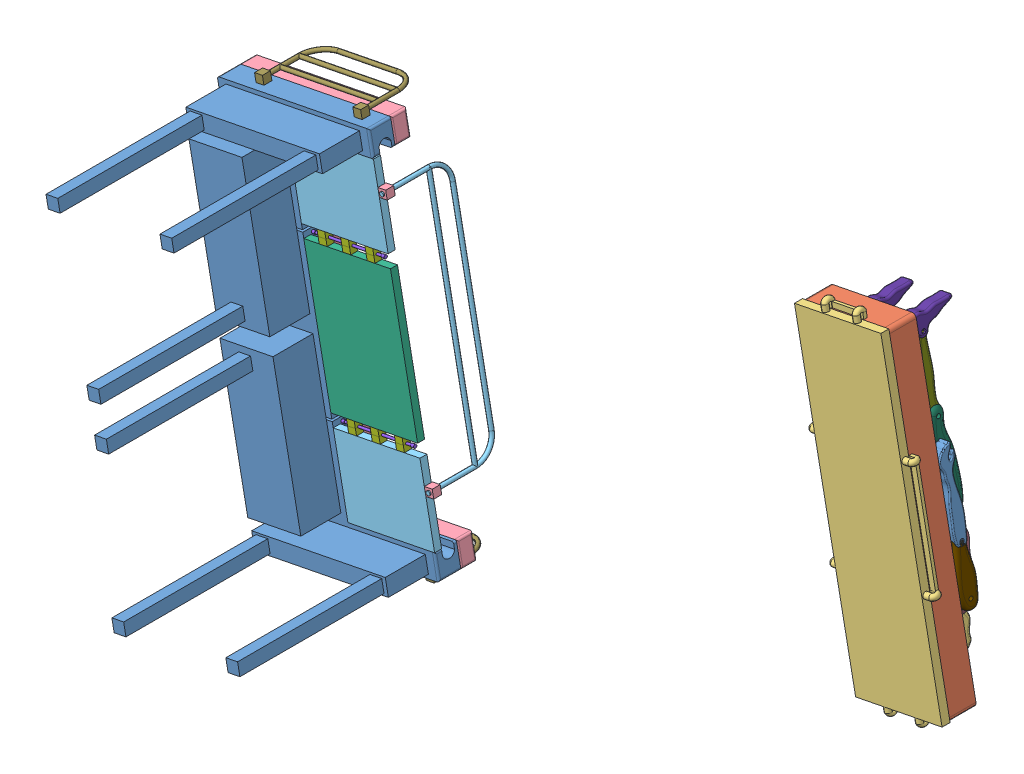
SolidWorks assembly Main_Bed_New, configuration Default. Lengths in mm.
Overall size (4670.43 3031.29 1745.74).
54 component instances, 23 part files, 74 mates.
Components (placement in the parent):
- Bed Matt-1: Bed Matt [Default] at (-2427.7538 2720.2704 -241.3) x (0.981103 0.193488 0) z (0 0 1) size (977.9 2311.4 1308.1)
- Strecher-1: Strecher [Default] at (1211.9857 3282.7447 -241.3) x (0.981103 0.193488 0) z (0 0 1) size (558.8 2006.6 169.05)
- Stretcher Plate-4: Stretcher Plate [Default] at (1600.2382 1314.064 -21.45) x (0.981103 0.193488 0) z (0 0 -1) size (724.37 2140.75 113.2)
- Bed Matteress-1: Bed Matteress [Default] at (-2427.7538 2720.2704 -241.3) x (0.981103 0.193488 0) z (0 0 1) size (977.9 2311.4 101.6)
- Bed_Plate_Small-1: Bed_Plate_Small [Default] at (-1692.2108 1156.6406 -44.45) x (0.981103 0.193488 0) z (0 0 1) size (560.57 482.6 44.45)
- Bed_Plate_Small-2: Bed_Plate_Small [Default] at (-1987.0861 2651.8411 -44.45) x (0.981103 0.193488 0) z (0 0 1) size (560.57 482.6 44.45)
- Bed_Plate_Large-1: Bed_Plate_Large [Default] at (-1878.9651 2103.6009 -44.45) x (0.981103 0.193488 0) z (0 0 1) size (560.57 889 44.45)
- Bed_Hinge-2: Bed_Hinge [Default] at (-1551.6324 1223.1985 0.01) x (0 0 -1) z (-0.981103 -0.193488 0) size (44.46 38.1 50.8)
- Bed_Hinge-3: Bed_Hinge [Default] at (-1601.4724 1213.3694 0.01) x (0 0 -1) z (0.981103 0.193488 0) size (44.46 38.1 50.8)
- Bed_Hinge-6: Bed_Hinge [Default] at (-1297.5562 1273.3061 0.01) x (0 0 -1) z (0.981103 0.193488 0) size (44.46 38.1 50.8)
- Bed_Hinge-7: Bed_Hinge [Default] at (-1247.7162 1283.1352 0.01) x (0 0 -1) z (-0.981103 -0.193488 0) size (44.46 38.1 50.8)
- Bed_Hinge-12: Bed_Hinge [Default] at (-1451.4787 1242.9503 0.01) x (0 0 -1) z (0.981103 0.193488 0) size (44.46 38.1 50.8)
- Bed_Hinge-13: Bed_Hinge [Default] at (-1401.6387 1252.7795 0.01) x (0 0 -1) z (-0.981103 -0.193488 0) size (44.46 38.1 50.8)
- Hinge Rod-1: Hinge Rod [Default] at (-1213.9368 1289.797 -22.22) x (0.177246 -0.898749 0.401041) z (0.981103 0.193488 0) size (20 20 470)
- Hinge Rod-2: Hinge Rod [Default] at (-1822.5654 2153.5576 -22.22) x (-0.177246 0.898749 0.401041) z (-0.981103 -0.193488 0) size (20 20 470)
- Bed_Hinge-14: Bed_Hinge [Default] at (-1738.3867 2170.1589 0.01) x (0 0 -1) z (-0.981103 -0.193488 0) size (44.46 38.1 50.8)
- Bed_Hinge-15: Bed_Hinge [Default] at (-1788.2268 2160.3297 0.01) x (0 0 -1) z (0.981103 0.193488 0) size (44.46 38.1 50.8)
- Bed_Hinge-16: Bed_Hinge [Default] at (-1588.3931 2199.7398 0.01) x (0 0 -1) z (-0.981103 -0.193488 0) size (44.46 38.1 50.8)
- Bed_Hinge-17: Bed_Hinge [Default] at (-1638.2331 2189.9106 0.01) x (0 0 -1) z (0.981103 0.193488 0) size (44.46 38.1 50.8)
- Bed_Hinge-18: Bed_Hinge [Default] at (-1434.4706 2230.0956 0.01) x (0 0 -1) z (-0.981103 -0.193488 0) size (44.46 38.1 50.8)
- Bed_Hinge-19: Bed_Hinge [Default] at (-1484.3106 2220.2664 0.01) x (0 0 -1) z (0.981103 0.193488 0) size (44.46 38.1 50.8)
- Roller_Small_Plate-1: Roller_Small_Plate [Default] at (-1548.0613 1392.1829 -40.4983) x (0.525896 0.103714 0.844202) z (-0.193488 0.981103 0) size (38.1 38.1 762)
- Roller_Small_Plate-2: Roller_Small_Plate [Default] at (-1639.7944 1374.0917 -40.4983) x (0.900265 0.177545 -0.397493) z (-0.193488 0.981103 0) size (38.1 38.1 762)
- Roller_Small_Plate-3: Roller_Small_Plate [Default] at (-1365.0169 1428.2819 -40.4983) x (-0.124546 -0.024562 -0.99191) z (-0.193488 0.981103 0) size (38.1 38.1 762)
- Roller_Small_Plate-4: Roller_Small_Plate [Default] at (-1273.2838 1446.373 -40.4983) x (0.980896 0.193447 -0.020528) z (-0.193488 0.981103 0) size (38.1 38.1 762)
- Roller_Big Plate-5: Roller_Big Plate [Default] at (-1831.4633 2345.9721 -40.4963) x (0.98109 0.193485 -0.005115) z (-0.193488 0.981103 0) size (38.1 38.1 304.8)
- Roller_Big Plate-6: Roller_Big Plate [Default] at (-1739.7302 2364.0632 -40.4963) x (0.98109 0.193485 -0.005115) z (-0.193488 0.981103 0) size (38.1 38.1 304.8)
- Roller_Big Plate-7: Roller_Big Plate [Default] at (-1464.9528 2418.2533 -40.4963) x (0.980987 0.193465 -0.015372) z (-0.193488 0.981103 0) size (38.1 38.1 304.8)
- Roller_Big Plate-8: Roller_Big Plate [Default] at (-1556.6859 2400.1622 -40.4963) x (0.980633 0.193395 -0.03093) z (-0.193488 0.981103 0) size (38.1 38.1 304.8)
- Roller_Big Plate-9: Roller_Big Plate [Default] at (-1536.588 850.7716 -40.4963) x (0.980896 0.193447 -0.020528) z (-0.193488 0.981103 0) size (38.1 38.1 304.8)
- Roller_Big Plate-10: Roller_Big Plate [Default] at (-1444.8549 868.8627 -40.4963) x (0.801443 0.158056 -0.576808) z (-0.193488 0.981103 0) size (38.1 38.1 304.8)
- Roller_Big Plate-11: Roller_Big Plate [Default] at (-1261.8106 904.9617 -40.4963) x (0.980778 0.193424 -0.025712) z (-0.193488 0.981103 0) size (38.1 38.1 304.8)
- Roller_Big Plate-12: Roller_Big Plate [Default] at (-1170.0775 923.0528 -40.4963) x (0.980778 0.193424 -0.025712) z (-0.193488 0.981103 0) size (38.1 38.1 304.8)
- Bed_Side_Handle-1: Bed_Side_Handle [Default] at (-2095.4954 904.2402 -100.8) x (-0.193488 0.981103 0) z (-0.981103 -0.193488 0) size (1574.8 393.7 50.8)
- Bed_Side_Handle_Small-1: Bed_Side_Handle_Small [Default] at (-2211.5278 2788.8026 -100.8) x (0.981103 0.193488 0) z (-0.193488 0.981103 0) size (685.8 393.7 50.8)
- Bed_Side_Handle_Small-2: Bed_Side_Handle_Small [Default] at (-1754.471 471.2418 -100.8) x (0.981103 0.193488 0) z (-0.193488 0.981103 0) size (685.8 393.7 50.8)
- Human_3D(10-04-12)-1: Human_3D(10-04-12) [Default] at (1738.9169 2054.8964 -241.3) x (0.981103 0.193488 0) z (0 0 -1) size (530.68 1832.11 366.32)
  - Chest_3D-1: Chest_3D [Default] at (-194.0697 -37.8635 128.1318) size (350.02 515.24 294.39)
  - Abdominal_3D-1: Abdominal_3D [Default] at (-147.423 -255.9077 128.1318) size (309.81 426.95 250.71)
  - Thigh_3D-1: Thigh_3D [Default] at (76.9303 -255.9077 128.1318) size (116.78 669.36 281.34)
  - Thigh_3D-2: Thigh_3D [Default] at (-173.0697 -255.9077 128.1318) size (116.78 669.36 281.34)
  - Leg_3D-1: Leg_3D [Default] at (-124.0697 -1124.992 128.1318) size (61.6 568.33 179.47)
  - Leg_3D-2: Leg_3D [Default] at (125.9303 -1124.992 128.1318) size (61.6 568.33 179.47)
  - Foot_3D-1: Foot_3D [Default] at (86.9303 -1224.992 128.1318) size (197.99 220.93 341.64)
  - Foot_3D-2: Foot_3D [Default] at (-163.0697 -1224.992 128.1318) size (197.99 220.93 341.64)
  - Arm_3D-1: Arm_3D [Default] at (176.9303 198.5522 92.8395) x (1 0 0) z (0 -0.000393 1) size (72.82 416.89 169.99)
  - Arm_3D-2: Arm_3D [Default] at (-243.0697 198.5522 92.8395) size (72.82 416.89 169.99)
  - Forearm_3D-1: Forearm_3D [Default] at (176.9303 -94.4478 92.7245) size (110.68 534.6 163.59)
  - Forearm_3D-2: Forearm_3D [Default] at (-243.0697 -94.4478 92.8395) size (110.68 534.6 163.59)
  - Neck_3D-1: Neck_3D [Default] at (-74.0697 -36.5687 126.8916) size (100.02 122.55 125.42)
  - Head_3D-1: Head_3D [Default] at (-89.0697 -36.6117 126.566) size (130.02 274.22 242.86)
- Bed_Handle_Rest-1: Bed_Handle_Rest [Default] at (-1114.3331 1123.629 0) x (0.981103 0.193488 0) z (0.193488 -0.981103 0) size (50.8 50.8 50.8)
- Bed_Handle_Rest-2: Bed_Handle_Rest [Default] at (-1409.2084 2618.8295 0) x (0.981103 0.193488 0) z (0.193488 -0.981103 0) size (50.8 50.8 50.8)
- Bed_Side_Adjustable_Handle-1: Bed_Side_Adjustable_Handle [Default] at (-1084.4985 1103.6236 7.0084) x (-0.193488 0.981103 0) z (-0.981103 -0.193488 0) size (1549.4 439.7 25.4)
Mates (geometry in assembly coordinates):
- Coincident6: coincident aligned: plane of Bed Matt-1 through (-2427.7538 2720.2704 0) normal (0 0 1); plane of assembly through (0 0 0) normal (0 0 1)
- Coincident8: coincident anti-aligned: plane of Bed Matt-1 through (-1438.8459 2759.962 0) normal (0.193488 -0.981103 0); plane of Strecher-1 through (1236.9057 3287.6593 -72.25) normal (-0.193488 0.981103 0)
- Parallel1: parallel anti-aligned: plane of Bed Matt-1 through (-1987.0861 2651.8411 0) normal (0.981103 0.193488 0); plane of Strecher-1 through (1216.9003 3257.8247 -72.25) normal (-0.981103 -0.193488 0)
- Coincident11: coincident aligned: plane of Bed Matt-1 through (-2427.7538 2720.2704 0) normal (0 0 1); plane of assembly through (0 0 0) normal (0 0 1)
- Coincident23: coincident anti-aligned: plane of Strecher-1 through (1620.2436 1343.8986 -72.25) normal (0 0 1); plane of Stretcher Plate-4 through (1600.2382 1314.064 -72.25) normal (0 0 -1)
- Coincident24: coincident aligned: plane of Strecher-1 through (1236.9057 3287.6593 -72.25) normal (-0.193488 0.981103 0); plane of Stretcher Plate-4 through (1211.9857 3282.7447 -72.25) normal (-0.193488 0.981103 0)
- Coincident25: coincident aligned: plane of Strecher-1 through (1216.9003 3257.8247 -72.25) normal (-0.981103 -0.193488 0); plane of Stretcher Plate-4 through (1600.2382 1314.064 -72.25) normal (-0.981103 -0.193488 0)
- Coincident26: coincident aligned: plane of Bed Matt-1 through (-2427.7538 2720.2704 0) normal (-0.193488 0.981103 0); plane of Bed Matteress-1 through (-2427.7538 2720.2704 -139.7) normal (-0.193488 0.981103 0)
- Coincident27: coincident anti-aligned: plane of Bed Matt-1 through (-2427.7538 2720.2704 -139.7) normal (0 0 -1); plane of Bed Matteress-1 through (-2427.7538 2720.2704 -139.7) normal (0 0 1)
- Coincident28: coincident aligned: plane of Bed Matt-1 through (-2427.7538 2720.2704 0) normal (-0.981103 -0.193488 0); plane of Bed Matteress-1 through (-2427.7538 2720.2704 -139.7) normal (-0.981103 -0.193488 0)
- Coincident29: coincident anti-aligned: plane of Bed Matt-1 through (-1987.0861 2651.8411 0) normal (0.981103 0.193488 0); plane of Bed_Plate_Small-1 through (-1692.2108 1156.6406 0) normal (-0.981103 -0.193488 0)
- Coincident30: coincident anti-aligned: plane of Bed Matt-1 through (-1598.8336 683.1604 0) normal (-0.193488 0.981103 0); plane of Bed_Plate_Small-1 through (-1598.8336 683.1604 0) normal (0.193488 -0.981103 0)
- Coincident31: coincident aligned: plane of Bed Matt-1 through (-2427.7538 2720.2704 0) normal (0 0 1); plane of Bed_Plate_Small-1 through (-1692.2108 1156.6406 0) normal (0 0 1)
- Coincident32: coincident aligned: plane of Bed Matt-1 through (-2427.7538 2720.2704 0) normal (0 0 1); plane of Bed_Plate_Small-2 through (-1987.0861 2651.8411 0) normal (0 0 1)
- Coincident34: coincident anti-aligned: plane of Bed Matt-1 through (-1987.0861 2651.8411 0) normal (0.981103 0.193488 0); plane of Bed_Plate_Small-2 through (-1987.0861 2651.8411 0) normal (-0.981103 -0.193488 0)
- Coincident35: coincident anti-aligned: plane of Bed Matt-1 through (-1438.8459 2759.962 0) normal (0.193488 -0.981103 0); plane of Bed_Plate_Small-2 through (-1987.0861 2651.8411 0) normal (-0.193488 0.981103 0)
- Coincident36: coincident aligned: plane of Bed Matt-1 through (-2427.7538 2720.2704 0) normal (0 0 1); plane of Bed_Plate_Large-1 through (-1878.9651 2103.6009 0) normal (0 0 1)
- Coincident37: coincident anti-aligned: plane of Bed Matt-1 through (-1987.0861 2651.8411 0) normal (0.981103 0.193488 0); plane of Bed_Plate_Large-1 through (-1878.9651 2103.6009 0) normal (-0.981103 -0.193488 0)
- Distance1: distance = 76.2 mm anti-aligned: plane of Bed_Plate_Large-1 through (-1878.9651 2103.6009 0) normal (-0.193488 0.981103 0); plane of Bed_Plate_Small-2 through (-1893.7089 2178.3609 0) normal (0.193488 -0.981103 0)
- Coincident45: coincident aligned: plane of Bed_Plate_Small-1 through (-1692.2108 1156.6406 -44.45) normal (0 0 -1); plane of Bed_Hinge-3 through (-1551.6324 1223.1985 -44.45) normal (0 0 -1)
- Coincident47: coincident anti-aligned: plane of Bed_Plate_Small-1 through (-1692.2108 1156.6406 0) normal (-0.193488 0.981103 0); plane of Bed_Hinge-3 through (-1544.2605 1185.8185 -44.45) normal (0.193488 -0.981103 0)
- Coincident48: coincident anti-aligned: plane of Bed_Plate_Large-1 through (-1706.9545 1231.4006 0) normal (0.193488 -0.981103 0); plane of Bed_Hinge-2 through (-1608.8443 1250.7494 -44.45) normal (-0.193488 0.981103 0)
- Coincident53: coincident aligned: plane of Bed_Plate_Large-1 through (-1878.9651 2103.6009 -44.45) normal (0 0 -1); plane of Bed_Hinge-2 through (-1601.4724 1213.3694 -44.45) normal (0 0 -1)
- Distance2: distance = 100 mm anti-aligned: plane of Bed Matt-1 through (-1987.0861 2651.8411 0) normal (0.981103 0.193488 0); plane of Bed_Hinge-3 through (-1601.4724 1213.3694 -22.22) normal (-0.981103 -0.193488 0)
- Coincident55: coincident aligned: plane of Bed_Hinge-2 through (-1551.6324 1223.1985 -22.22) normal (0.981103 0.193488 0); plane of Bed_Hinge-3 through (-1551.6324 1223.1985 -22.22) normal (0.981103 0.193488 0)
- Concentric1: concentric anti-aligned: cylinder of Bed_Hinge-6 through (-1247.7162 1283.1352 -22.22) axis (-0.981103 -0.193488 0) radius 7.41; cylinder of Hinge Rod-1 through (-1635.811 1206.5973 -22.22) axis (0.981103 0.193488 0) radius 7.41
- Distance4: distance = 45 mm anti-aligned: plane of Hinge Rod-1 through (-1655.433 1202.7275 -22.22) normal (-0.981103 -0.193488 0); plane of Bed Matt-1 through (-1987.0861 2651.8411 0) normal (0.981103 0.193488 0)
- Concentric2: concentric aligned: cylinder of Bed_Plate_Large-1 through (-1774.9456 2059.392 -40.4983) axis (0.193488 -0.981103 0) radius 19.05; cylinder of Roller_Small_Plate-2 through (-1762.6591 1997.092 -40.4983) axis (0.193488 -0.981103 0) radius 19.05
- Coincident58: coincident anti-aligned: plane of Bed_Plate_Large-1 through (-1627.5079 1311.7917 -40.4983) normal (-0.193488 0.981103 0); plane of Roller_Small_Plate-2 through (-1627.5079 1311.7917 -40.4983) normal (0.193488 -0.981103 0)
- Concentric3: concentric aligned: cylinder of Bed_Plate_Large-1 through (-1683.2125 2077.4831 -40.4983) axis (0.193488 -0.981103 0) radius 19.05; cylinder of Roller_Small_Plate-1 through (-1670.926 2015.1831 -40.4983) axis (0.193488 -0.981103 0) radius 19.05
- Coincident59: coincident anti-aligned: plane of Bed_Plate_Large-1 through (-1683.2125 2077.4831 -40.4983) normal (0.193488 -0.981103 0); plane of Roller_Small_Plate-1 through (-1683.2125 2077.4831 -40.4983) normal (-0.193488 0.981103 0)
- Concentric4: concentric aligned: cylinder of Bed_Plate_Large-1 through (-1500.1681 2113.5821 -40.4983) axis (0.193488 -0.981103 0) radius 19.05; cylinder of Roller_Small_Plate-3 through (-1487.8817 2051.2821 -40.4983) axis (0.193488 -0.981103 0) radius 19.05
- Coincident60: coincident anti-aligned: plane of Bed_Plate_Large-1 through (-1352.7305 1365.9818 -40.4983) normal (-0.193488 0.981103 0); plane of Roller_Small_Plate-3 through (-1352.7305 1365.9818 -40.4983) normal (0.193488 -0.981103 0)
- Concentric5: concentric aligned: cylinder of Bed_Plate_Large-1 through (-1408.435 2131.6732 -40.4983) axis (0.193488 -0.981103 0) radius 19.05; cylinder of Roller_Small_Plate-4 through (-1396.1486 2069.3732 -40.4983) axis (0.193488 -0.981103 0) radius 19.05
- Coincident61: coincident anti-aligned: plane of Bed_Plate_Large-1 through (-1260.9974 1384.0729 -40.4983) normal (-0.193488 0.981103 0); plane of Roller_Small_Plate-4 through (-1260.9974 1384.0729 -40.4983) normal (0.193488 -0.981103 0)
- Concentric6: concentric anti-aligned: cylinder of Bed_Plate_Small-2 through (-1819.1769 2283.672 -40.4963) axis (-0.193488 0.981103 0) radius 19.05; cylinder of Roller_Big Plate-5 through (-1865.8655 2520.4121 -40.4963) axis (0.193488 -0.981103 0) radius 19.05
- Coincident62: coincident anti-aligned: plane of Bed_Plate_Small-2 through (-1878.1519 2582.7121 -40.4963) normal (0.193488 -0.981103 0); plane of Roller_Big Plate-5 through (-1878.1519 2582.7121 -40.4963) normal (-0.193488 0.981103 0)
- Concentric7: concentric anti-aligned: cylinder of Bed_Plate_Small-2 through (-1727.4438 2301.7632 -40.4963) axis (-0.193488 0.981103 0) radius 19.05; cylinder of Roller_Big Plate-6 through (-1774.1324 2538.5032 -40.4963) axis (0.193488 -0.981103 0) radius 19.05
- Coincident63: coincident anti-aligned: plane of Bed_Plate_Small-2 through (-1786.4188 2600.8033 -40.4963) normal (0.193488 -0.981103 0); plane of Roller_Big Plate-6 through (-1786.4188 2600.8033 -40.4963) normal (-0.193488 0.981103 0)
- Concentric8: concentric anti-aligned: cylinder of Bed_Plate_Small-2 through (-1544.3994 2337.8622 -40.4963) axis (-0.193488 0.981103 0) radius 19.05; cylinder of Roller_Big Plate-8 through (-1591.088 2574.6022 -40.4963) axis (0.193488 -0.981103 0) radius 19.05
- Coincident64: coincident anti-aligned: plane of Bed_Plate_Small-2 through (-1603.3745 2636.9023 -40.4963) normal (0.193488 -0.981103 0); plane of Roller_Big Plate-8 through (-1603.3745 2636.9023 -40.4963) normal (-0.193488 0.981103 0)
- Concentric9: concentric anti-aligned: cylinder of Bed_Plate_Small-2 through (-1452.6663 2355.9533 -40.4963) axis (-0.193488 0.981103 0) radius 19.05; cylinder of Roller_Big Plate-7 through (-1499.3549 2592.6933 -40.4963) axis (0.193488 -0.981103 0) radius 19.05
- Coincident65: coincident anti-aligned: plane of Bed_Plate_Small-2 through (-1511.6414 2654.9934 -40.4963) normal (0.193488 -0.981103 0); plane of Roller_Big Plate-7 through (-1511.6414 2654.9934 -40.4963) normal (-0.193488 0.981103 0)
- Concentric10: concentric anti-aligned: cylinder of Bed_Plate_Small-1 through (-1524.3015 788.4715 -40.4963) axis (-0.193488 0.981103 0) radius 19.05; cylinder of Roller_Big Plate-9 through (-1570.9901 1025.2116 -40.4963) axis (0.193488 -0.981103 0) radius 19.05
- Coincident66: coincident anti-aligned: plane of Bed_Plate_Small-1 through (-1524.3015 788.4715 -40.4963) normal (-0.193488 0.981103 0); plane of Roller_Big Plate-9 through (-1524.3015 788.4715 -40.4963) normal (0.193488 -0.981103 0)
- Concentric11: concentric anti-aligned: cylinder of Bed_Plate_Small-1 through (-1432.5684 806.5627 -40.4963) axis (-0.193488 0.981103 0) radius 19.05; cylinder of Roller_Big Plate-10 through (-1479.257 1043.3027 -40.4963) axis (0.193488 -0.981103 0) radius 19.05
- Coincident67: coincident anti-aligned: plane of Bed_Plate_Small-1 through (-1432.5684 806.5627 -40.4963) normal (-0.193488 0.981103 0); plane of Roller_Big Plate-10 through (-1432.5684 806.5627 -40.4963) normal (0.193488 -0.981103 0)
- Concentric12: concentric anti-aligned: cylinder of Bed_Plate_Small-1 through (-1249.5241 842.6617 -40.4963) axis (-0.193488 0.981103 0) radius 19.05; cylinder of Roller_Big Plate-11 through (-1296.2127 1079.4017 -40.4963) axis (0.193488 -0.981103 0) radius 19.05
- Coincident68: coincident anti-aligned: plane of Bed_Plate_Small-1 through (-1308.4992 1141.7018 -40.4963) normal (0.193488 -0.981103 0); plane of Roller_Big Plate-11 through (-1308.4992 1141.7018 -40.4963) normal (-0.193488 0.981103 0)
- Concentric13: concentric anti-aligned: cylinder of Bed_Plate_Small-1 through (-1157.791 860.7528 -40.4963) axis (-0.193488 0.981103 0) radius 19.05; cylinder of Roller_Big Plate-12 through (-1204.4796 1097.4929 -40.4963) axis (0.193488 -0.981103 0) radius 19.05
- Coincident69: coincident anti-aligned: plane of Bed_Plate_Small-1 through (-1216.7661 1159.7929 -40.4963) normal (0.193488 -0.981103 0); plane of Roller_Big Plate-12 through (-1216.7661 1159.7929 -40.4963) normal (-0.193488 0.981103 0)
- Coincident70: coincident anti-aligned: plane of Bed Matt-1 through (-2427.7538 2720.2704 0) normal (-0.981103 -0.193488 0); plane of Bed_Side_Handle-1 through (-2075.49 934.0748 -50) normal (0.981103 0.193488 0)
- Distance5: distance = 50 mm aligned: plane of Bed_Side_Handle-1 through (-2095.4954 904.2402 -50) normal (0 0 1); plane of Bed Matt-1 through (-2427.7538 2720.2704 0) normal (0 0 1)
- Distance6: distance = 440 mm aligned: plane of Bed_Side_Handle-1 through (-2115.5008 874.4057 -50) normal (0.193488 -0.981103 0); plane of Bed Matt-1 through (-1980.5262 452.5496 0) normal (0.193488 -0.981103 0)
- Coincident75: coincident anti-aligned: plane of Bed Matt-1 through (-2427.7538 2720.2704 0) normal (-0.193488 0.981103 0); plane of Bed_Side_Handle_Small-1 through (-2181.6932 2768.7971 -50) normal (0.193488 -0.981103 0)
- Distance7: distance = 200 mm aligned: plane of Bed_Side_Handle_Small-1 through (-2241.3624 2808.808 -50) normal (-0.981103 -0.193488 0); plane of Bed Matt-1 through (-2427.7538 2720.2704 0) normal (-0.981103 -0.193488 0)
- Coincident77: coincident aligned: plane of Bed_Side_Handle-1 through (-2095.4954 904.2402 -50) normal (0 0 1); plane of Bed_Side_Handle_Small-1 through (-2211.5278 2788.8026 -50) normal (0 0 1)
- Coincident78: coincident anti-aligned: plane of Bed Matt-1 through (-1980.5262 452.5496 0) normal (0.193488 -0.981103 0); plane of Bed_Side_Handle_Small-2 through (-1734.4656 501.0764 -50) normal (-0.193488 0.981103 0)
- Distance8: distance = 200 mm aligned: plane of Bed_Side_Handle_Small-2 through (-1784.3056 491.2472 -50) normal (-0.981103 -0.193488 0); plane of Bed Matt-1 through (-2427.7538 2720.2704 0) normal (-0.981103 -0.193488 0)
- Coincident80: coincident aligned: plane of Bed_Side_Handle-1 through (-2095.4954 904.2402 -50) normal (0 0 1); plane of Bed_Side_Handle_Small-2 through (-1754.471 471.2418 -50) normal (0 0 1)
- Coincident81: coincident aligned: plane of Strecher-1 through (1620.2436 1343.8986 -241.3) normal (0 0 -1); plane of Human_3D(10-04-12)-1 through (1738.9169 2054.8964 -241.3) normal (0 0 -1)
- Coincident82: coincident aligned: plane of Strecher-1; plane of Human_3D(10-04-12)-1
- Coincident83: coincident aligned: plane of Strecher-1; plane of Human_3D(10-04-12)-1
- Coincident86: coincident aligned: plane of Strecher-1 through (1620.2436 1343.8986 -241.3) normal (0 0 -1); plane of Bed Matteress-1 through (-2427.7538 2720.2704 -241.3) normal (0 0 -1)
- Coincident87: coincident anti-aligned: plane of Bed_Plate_Large-1 through (-1328.9884 2212.0643 0) normal (0.981103 0.193488 0); plane of Bed_Handle_Rest-2 through (-1399.3793 2568.9895 0) normal (-0.981103 -0.193488 0)
- Coincident88: coincident aligned: plane of Bed_Side_Handle-1 through (-2420.2053 2419.4462 -50) normal (-0.193488 0.981103 0); plane of Bed_Handle_Rest-2 through (-1409.2084 2618.8295 0) normal (-0.193488 0.981103 0)
- Coincident89: coincident aligned: plane of Bed_Plate_Small-2 through (-1987.0861 2651.8411 0) normal (0 0 1); plane of Bed_Handle_Rest-2 through (-1399.3793 2568.9895 0) normal (0 0 1)
- Coincident90: coincident anti-aligned: plane of Bed_Plate_Small-1 through (-1142.234 1265.104 0) normal (0.981103 0.193488 0); plane of Bed_Handle_Rest-1 through (-1104.5039 1073.789 0) normal (-0.981103 -0.193488 0)
- Coincident91: coincident aligned: plane of Bed_Side_Handle-1 through (-2115.5008 874.4057 -50) normal (0.193488 -0.981103 0); plane of Bed_Handle_Rest-1 through (-1104.5039 1073.789 0) normal (0.193488 -0.981103 0)
- Coincident92: coincident aligned: plane of Bed_Plate_Small-1 through (-1692.2108 1156.6406 0) normal (0 0 1); plane of Bed_Handle_Rest-1 through (-1104.5039 1073.789 0) normal (0 0 1)
- Concentric14: concentric aligned: cylinder of Bed_Handle_Rest-2 through (-1379.3738 2598.8241 -50.801) axis (0 0 1) radius 12.7; cylinder of Bed_Side_Adjustable_Handle-1 through (-1379.3738 2598.8241 -292.9916) axis (0 0 1) radius 12.7
- Concentric15: concentric aligned: cylinder of Bed_Handle_Rest-1 through (-1084.4985 1103.6236 -50.801) axis (0 0 1) radius 12.7; cylinder of Bed_Side_Adjustable_Handle-1 through (-1084.4985 1103.6236 -292.9916) axis (0 0 1) radius 12.7
- Coincident94: coincident aligned: plane of Bed_Handle_Rest-2 through (-1399.3793 2568.9895 0) normal (0 0 1); plane of Bed_Side_Adjustable_Handle-1 through (-1379.3738 2598.8241 0) normal (0 0 1)
- Coincident95: coincident aligned: plane of Stretcher Plate-4 through (-1048.8568 791.6238 -72.25) normal (0.981103 0.193488 0); plane of Bed_Plate_Small-2 through (-1437.1094 2760.3045 0) normal (0.981103 0.193488 0)
